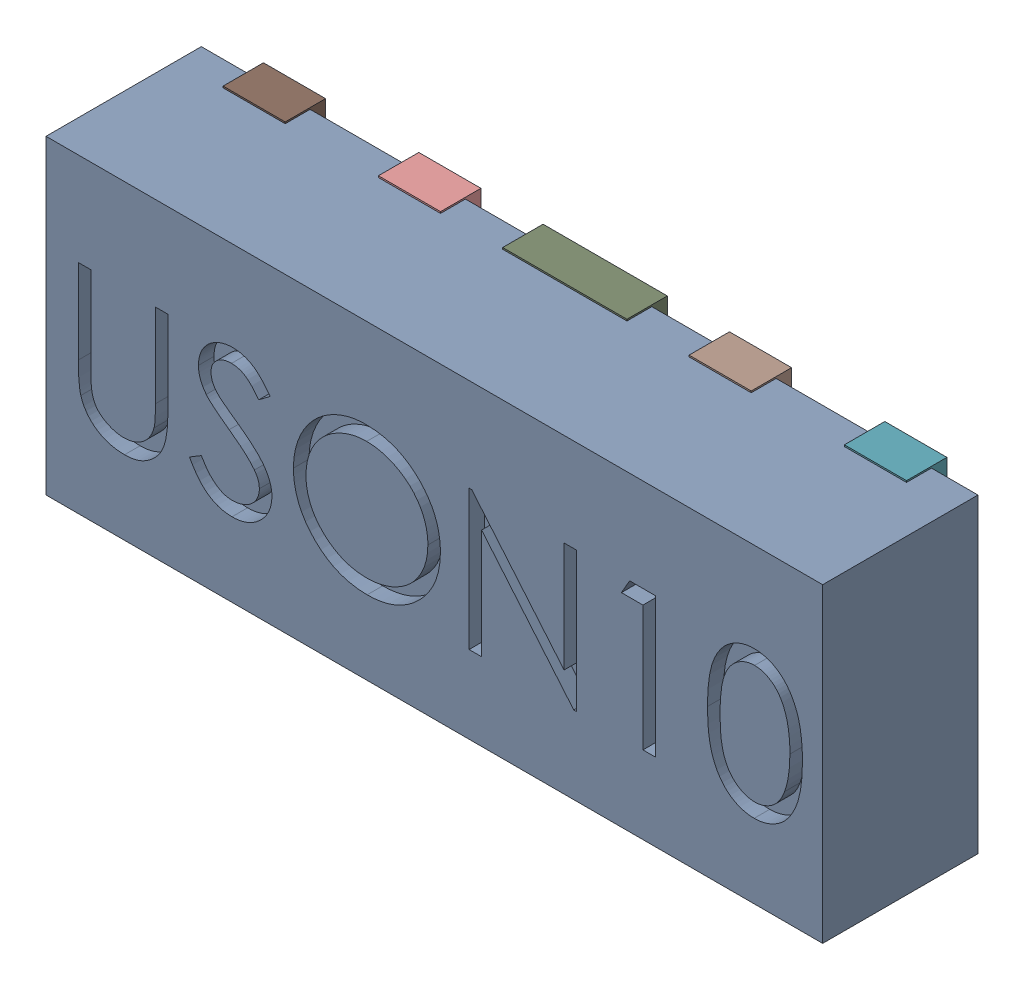
SolidWorks assembly D9, configuration Défaut. Lengths in mm.
Overall size (2.5 1.01 0.55).
12 component instances, 5 part files, 0 mates.
Components (placement in the parent):
- UDFN10-1: UDFN10 [Défaut] at (35.3958 -33.7093 -0.9099) x (1 0 0) z (0 -1 0) size (2.5 0.55 1.01)
  - User Library-UDFN10_Body-1: User Library-UDFN10_Body [Défaut] at (1.0785 0.9721 1.8983) size (2.5 0.5 1)
  - User Library-UDFN10_Pin1-1: User Library-UDFN10_Pin1 [Défaut] at (0.0785 1.0521 2.2208) x (0 0 -1) z (-1 0 0) size (0.37 0.13 0.2)
  - User Library-UDFN10_Pin2-1: User Library-UDFN10_Pin2 [Défaut] at (0.5785 1.0521 2.2208) x (0 0 1) z (1 0 0) size (0.37 0.13 0.2)
  - User Library-UDFN10_Pin4-1: User Library-UDFN10_Pin4 [Défaut] at (1.0785 0.9221 2.2208) x (0 0 1) z (-1 0 0) size (0.49 0.13 0.4)
  - User Library-UDFN10_Pin2-2: User Library-UDFN10_Pin2 [Défaut] at (1.5785 0.9221 2.2208) x (0 0 1) z (-1 0 0) size (0.37 0.13 0.2)
  - User Library-UDFN10_Pin2-3: User Library-UDFN10_Pin2 [Défaut] at (2.0785 0.9221 2.2208) x (0 0 1) z (-1 0 0) size (0.37 0.13 0.2)
  - User Library-UDFN10_Pin2-4: User Library-UDFN10_Pin2 [Défaut] at (2.0785 0.9221 1.5758) x (0 0 -1) z (1 0 0) size (0.37 0.13 0.2)
  - User Library-UDFN10_Pin2-5: User Library-UDFN10_Pin2 [Défaut] at (1.5785 0.9221 1.5758) x (0 0 -1) z (1 0 0) size (0.37 0.13 0.2)
  - User Library-UDFN10_Pin3-1: User Library-UDFN10_Pin3 [Défaut] at (1.0785 0.9221 1.5758) x (0 0 1) z (-1 0 0) size (0.37 0.13 0.4)
  - User Library-UDFN10_Pin2-6: User Library-UDFN10_Pin2 [Défaut] at (0.5785 0.9221 1.5758) x (0 0 -1) z (1 0 0) size (0.37 0.13 0.2)
  - User Library-UDFN10_Pin2-7: User Library-UDFN10_Pin2 [Défaut] at (0.0785 0.9221 1.5758) x (0 0 -1) z (1 0 0) size (0.37 0.13 0.2)
